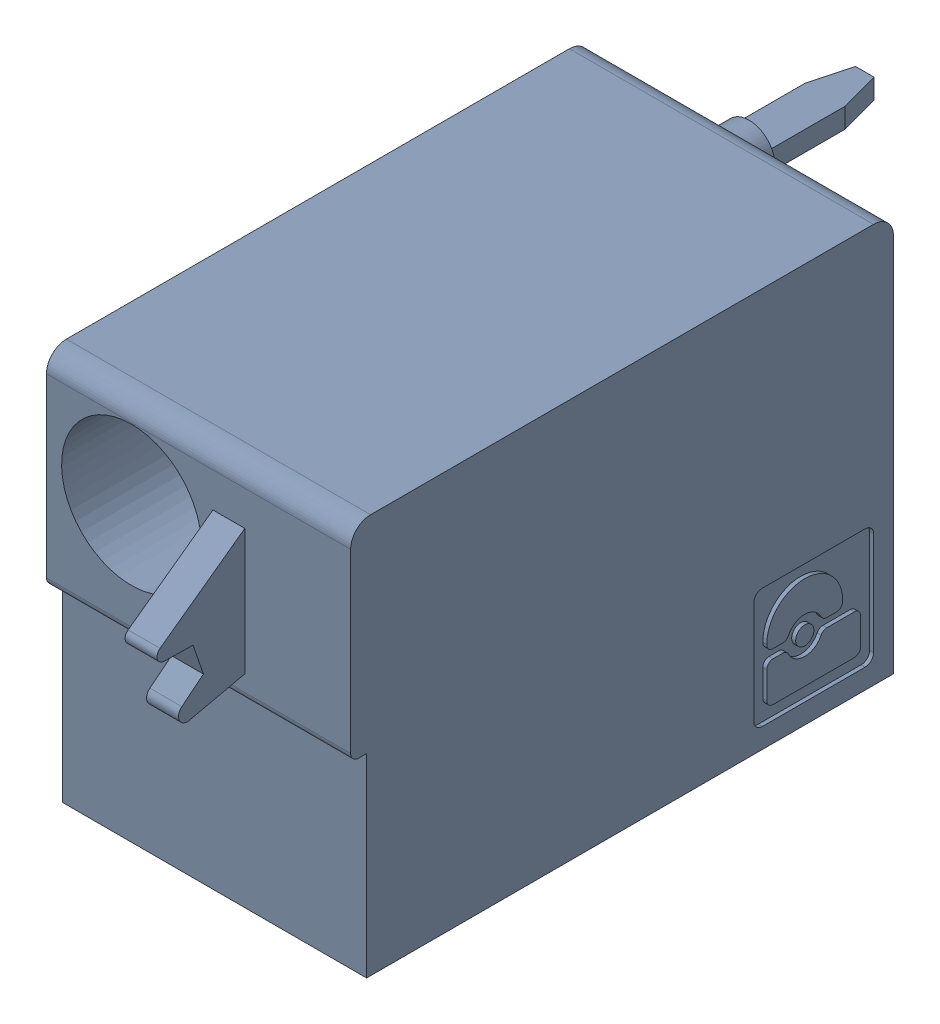
SolidWorks assembly J14, configuration Default. Lengths in mm.
Overall size (7.62 10 19.2).
2 component instances, 1 part files, 0 mates.
Components (placement in the parent):
- 1790487-1: 1790487 [Default] at (18.185 -5.67 -10.6) x (0 1 0) z (1 0 0) size (10 19.2 7.62)
  - ffkdsa1-v2-7.62-1: ffkdsa1-v2-7.62 [Default] at (-15.6914 -27.508 9.12) x (0 -1 0) z (0 0 1) size (19.2 10 7.62)
